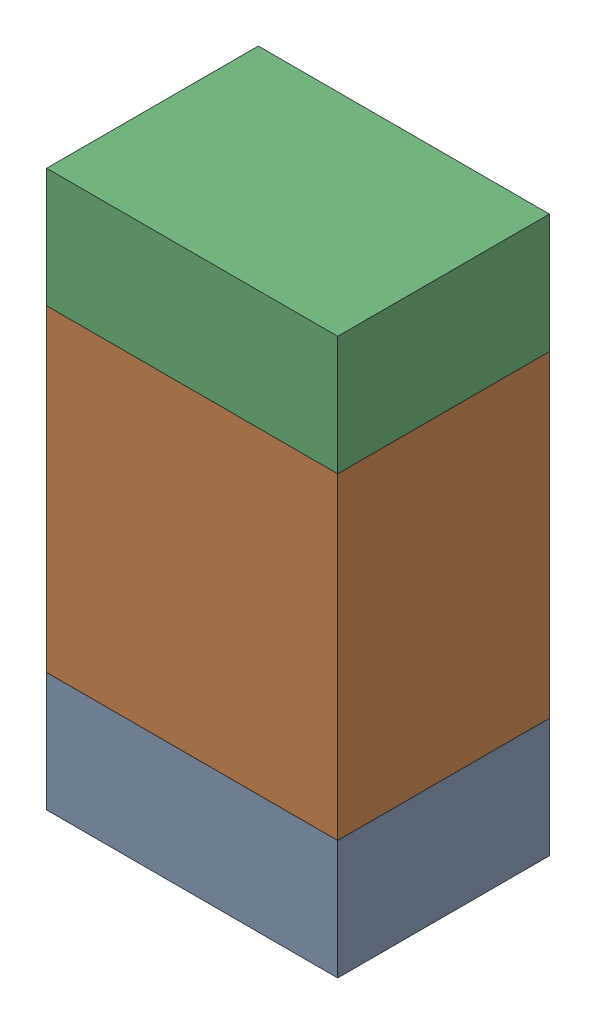
SolidWorks assembly R208PCB, configuration Default. Lengths in mm.
Overall size (0.55 1.05 0.4).
6 component instances, 2 part files, 0 mates.
Components (placement in the parent):
- 846483288-1: 846483288 [Default] at (93.2999 125.4876 0) size (0.55 0.22 0.4)
  - Extruded_12-1: Extruded_12 [Default] at origin size (0.55 0.22 0.4)
- 846483424-1: 846483424 [Default] at (93.2999 125.9001 0) size (0.55 0.6 0.4)
  - Extruded_13-1: Extruded_13 [Default] at origin size (0.55 0.6 0.4)
- 846483288-2: 846483288 [Default] at (93.2999 126.3126 0) size (0.55 0.22 0.4)
  - Extruded_12-1: Extruded_12 [Default] at origin size (0.55 0.22 0.4)
